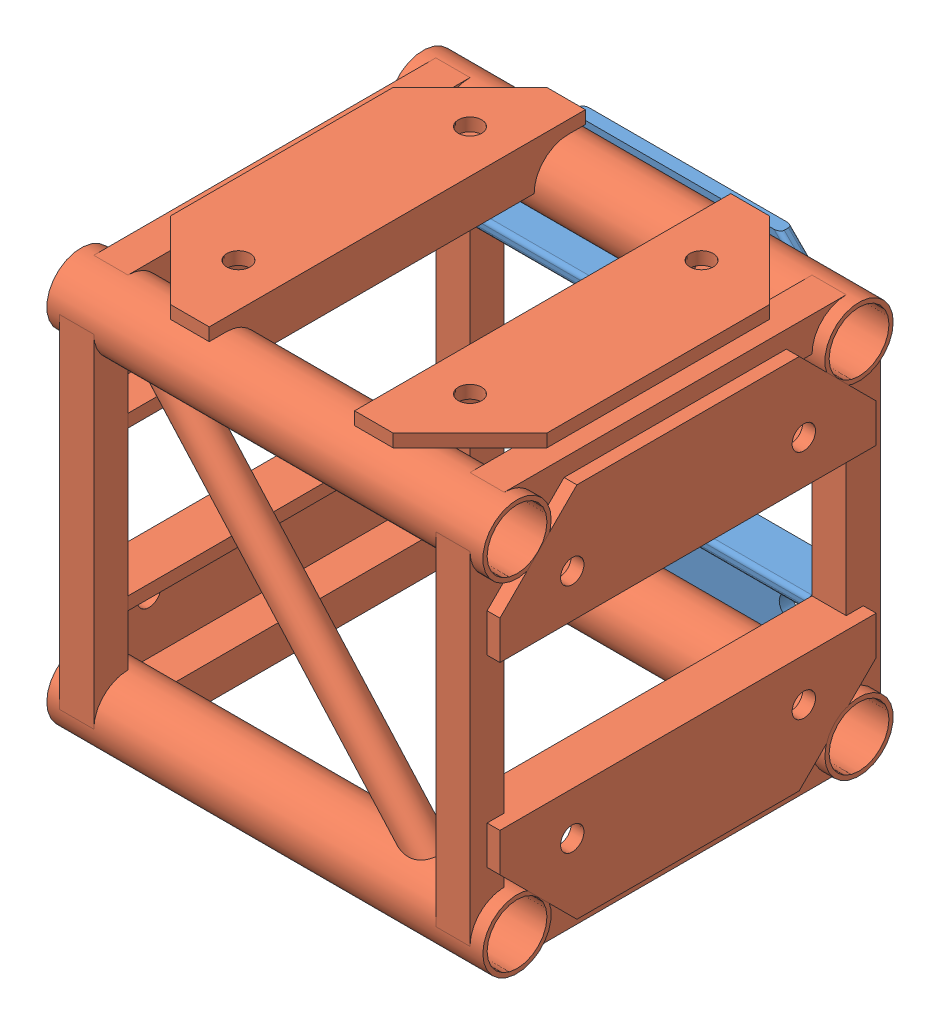
SolidWorks assembly GE-20002, configuration Default. Lengths in mm.
Overall size (323.85 314.33 314.32).
3 component instances, 2 part files, 6 mates.
Components (placement in the parent):
- Connection Plate _ TS Standard-1: Connection Plate _ TS Standard [Default] at (-13576.8315 -2437.9314 3196.1374) size (273.05 85.72 34.92)
- Connection Plate _ TS Standard-2: Connection Plate _ TS Standard [Default] at (-13576.8315 -2238.9859 3196.1374) x (-1 0 0) z (0 0 1) size (273.05 85.72 34.92)
- GE-20002 - 01-1: GE-20002 - 01 [Default] at (-13576.8315 -2333.6962 3340.5999) size (323.85 314.33 304.8)
Mates (geometry in assembly coordinates):
- Coincident1: coincident anti-aligned: plane of LDC123TN 3D_KC-1 through (-13729.2315 -2211.4587 3188.1999) normal (0 0 -1); plane of Connection Plate _ TS Standard-2 through (-13576.8315 -2234.3151 3188.1999) normal (0 0 1)
- Coincident2: coincident anti-aligned: plane of LDC123TN 3D_KC-1 through (-13424.4315 -2211.4587 3188.1999) normal (0 0 -1); plane of Connection Plate _ TS Standard-1 through (-13576.8315 -2433.2606 3188.1999) normal (0 0 1)
- Width1: width anti-aligned: plane of LDC123TN 3D_KC-1 through (-13424.4315 -2211.4587 3213.5999) normal (1 0 0); plane of LDC123TN 3D_KC-1 through (-13729.2315 -2211.4587 3213.5999) normal (-1 0 0); plane of Connection Plate _ TS Standard-2 through (-13700.6565 -2277.1776 3213.5999) normal (-1 0 0); plane of Connection Plate _ TS Standard-2 through (-13453.0065 -2267.6526 3213.5999) normal (1 0 0)
- Width2: width anti-aligned: plane of Connection Plate _ TS Standard-1 through (-13700.6565 -2399.9231 3213.5999) normal (-1 0 0); plane of Connection Plate _ TS Standard-1 through (-13453.0065 -2390.3981 3213.5999) normal (1 0 0); plane of LDC123TN 3D_KC-1 through (-13424.4315 -2211.4587 3213.5999) normal (1 0 0); plane of LDC123TN 3D_KC-1 through (-13729.2315 -2211.4587 3213.5999) normal (-1 0 0)
- Distance1: distance = 171.958 mm: cylinder of Connection Plate _ TS Standard-1 through (-13490.8525 -2433.1689 3178.6749) axis (0 0 -1) radius 8.7312; cylinder of Connection Plate _ TS Standard-2 through (-13490.8525 -2243.7484 3178.6749) axis (0 0 -1) radius 8.7312
- Width3: width anti-aligned: plane of GE-20002 - 01-1 through (-13424.4315 -2186.0587 3467.5999) normal (0 1 0); plane of Connection Plate _ TS Standard-1 through (-13424.4315 -2490.8587 3213.5999) normal (0 -1 0); plane of GE-20002 - 01-1 through (-13654.619 -2480.7939 3178.6749) normal (0 -1 0); plane of Connection Plate _ TS Standard-2 through (-13499.044 -2196.1234 3178.6749) normal (0 1 0)
